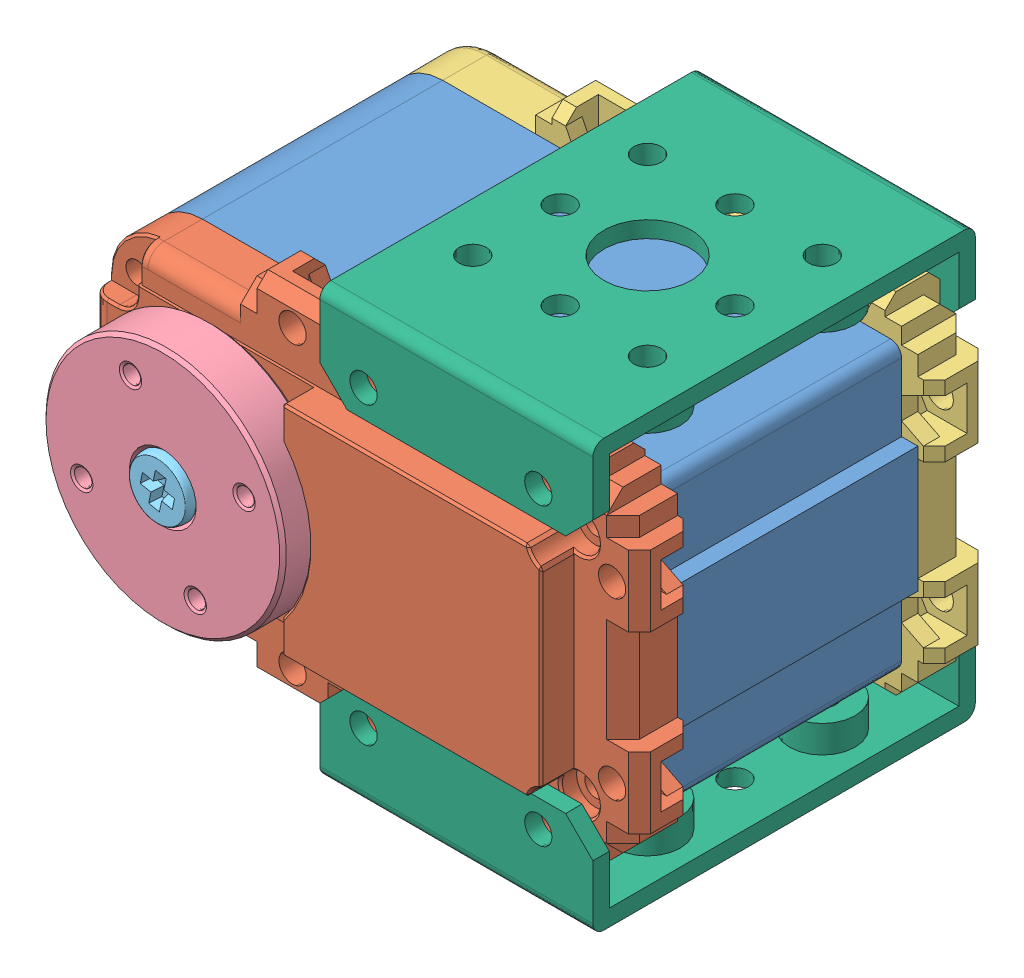
SolidWorks assembly try1, configuration Default. Lengths in mm.
Overall size (52.79 39 40.62).
7 component instances, 6 part files, 17 mates.
Components (placement in the parent):
- AX-12A-01-1: AX-12A-01 [Default] at (9.2833 28.9443 32.6852) size (48.5 26 22)
- AX-12A-02-1: AX-12A-02 [Default] at (9.2833 28.9443 46.1852) size (50 32 8)
- AX-12A-03-2: AX-12A-03 [Default] at (9.2833 28.9443 19.1852) x (1 0 0) z (0 0 -1) size (50 32 8)
- AX-12A-04-1: AX-12A-04 [Default] at (9.2833 28.9443 53.8031) x (0.370756 -0.92873 0) z (0 0 1) size (22 22 6.7)
- Screw1-1: Screw1 [Default] at (9.2833 28.9443 52.3046) x (0.978763 -0.204994 0) z (-0.204994 -0.978763 0) size (5.62 9.5 5.62)
- servovas-1: servovas [Default] at (20.0333 9.4443 15.1852) x (0 0 1) z (0 1 0) size (35 25 8.5)
- servovas-2: servovas [Default] at (20.0333 48.4443 50.1852) x (0 0 -1) z (0 -1 0) size (35 25 8.5)
Mates (geometry in assembly coordinates):
- Coincident2: coincident: plane of AX-12A-01-1 through (44.7833 15.9443 43.6852) normal (0 -1 0); plane of AX-12A-02-1 through (11.2833 15.9443 48.6852) normal (0 -1 0)
- Coincident3: coincident: plane of AX-12A-01-1 through (-2.2167 15.9443 43.6852) normal (-1 0 0); plane of AX-12A-02-1 through (-2.2167 15.9443 48.6852) normal (-1 0 0)
- Coincident12: coincident: plane of AX-12A-01-1 through (9.2833 28.9443 21.6852) normal (0 0 -1); plane of AX-12A-03-2 through (9.2833 28.9443 21.6852) normal (0 0 1)
- Coincident13: coincident: plane of AX-12A-01-1 through (-2.2167 15.9443 43.6852) normal (-1 0 0); plane of AX-12A-03-2 through (-2.2167 41.9443 16.6852) normal (-1 0 0)
- Coincident14: coincident: plane of AX-12A-01-1 through (44.7833 15.9443 43.6852) normal (0 -1 0); plane of AX-12A-03-2 through (11.2833 15.9443 16.6852) normal (0 -1 0)
- Concentric7: concentric: cylinder of AX-12A-02-1 through (9.2833 28.9443 46.4352) axis (0 0 1) radius 4.75; cylinder of AX-12A-04-1 through (9.2833 28.9443 53.8031) axis (0 0 -1) radius 4.5
- Concentric2: concentric: cylinder of AX-12A-04-1 through (9.2833 28.9443 53.8031) axis (0 0 -1) radius 1.25; cylinder of Screw1-1 through (9.2833 28.9443 44.8046) axis (0 0 1) radius 1
- Coincident21: coincident: plane of AX-12A-01-1 through (9.2833 28.9443 43.6852) normal (0 0 1); plane of AX-12A-02-1 through (9.2833 28.9443 43.6852) normal (0 0 -1)
- Tangent2: tangent: plane of AX-12A-04-1 through (6.7293 27.9247 53.9352) normal (0 0 1); face of Screw1-1
- Coincident22: coincident: plane of AX-12A-02-1 through (9.2833 28.9443 46.4352) normal (0 0 1); circle of Screw1-1
- Concentric8: concentric: circle of AX-12A-03-2; circle of servovas-1
- Concentric9: concentric: circle of AX-12A-03-2; circle of servovas-1
- Coincident26: coincident: plane of AX-12A-03-2 through (9.2833 28.9443 16.6852) normal (0 0 -1); plane of servovas-1 through (45.0333 10.9443 16.6852) normal (0 0 1)
- Concentric10: concentric: circle of AX-12A-02-1; circle of servovas-2
- Concentric11: concentric: circle of AX-12A-02-1; circle of servovas-2
- Coincident28: coincident: plane of AX-12A-02-1 through (9.2833 28.9443 48.6852) normal (0 0 1); plane of servovas-2 through (45.0333 46.9443 48.6852) normal (0 0 -1)
- Coincident29: coincident: plane of AX-12A-01-1 through (9.2833 28.9443 43.6852) normal (0 0 1); plane of AX-12A-02-1 through (9.2833 28.9443 43.6852) normal (0 0 -1)
